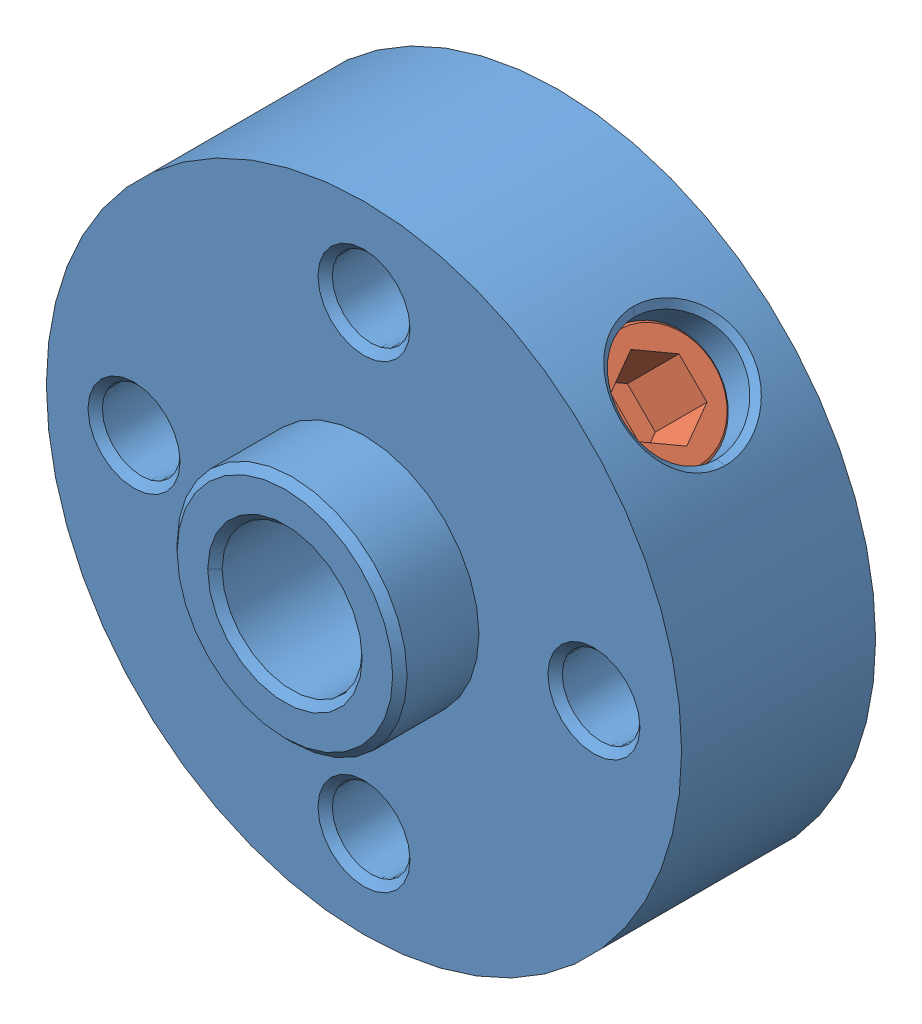
SolidWorks assembly Tetrix Axle Hub, configuration Default. Lengths in mm.
Overall size (22.1 22.1 9.5).
2 component instances, 2 part files, 0 mates.
Components (placement in the parent):
- Tetrix Axle Hub Body-1: Tetrix Axle Hub Body [Default] at origin size (22.1 22.1 9.5)
- Tetrix Axle Hub Set Screw-1: Tetrix Axle Hub Set Screw [Default] at (6.9308 6.9308 -3.325) x (-0.707107 0.707107 0) z (0 0 1) size (4.83 7.94 4.83)
